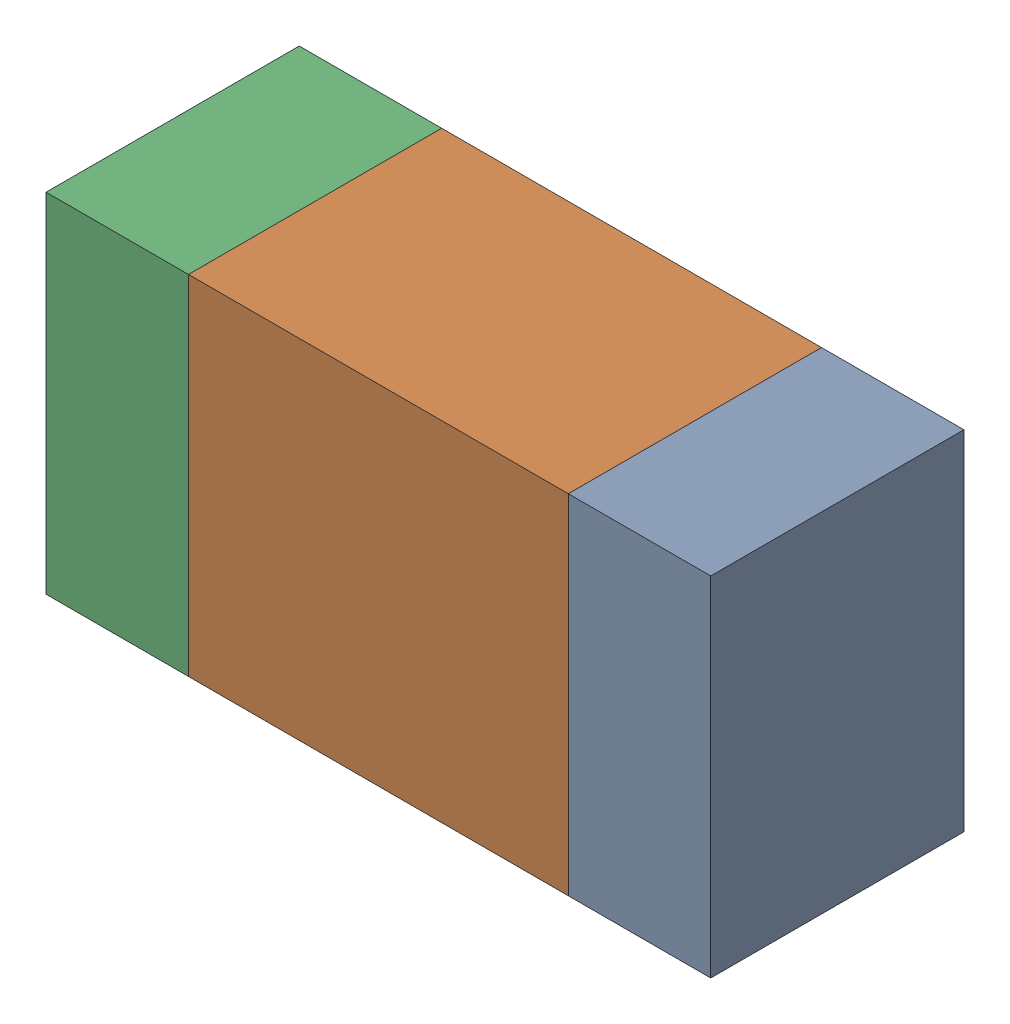
SolidWorks assembly R315_1PCB, configuration Default. Lengths in mm.
Overall size (1.05 0.55 0.4).
6 component instances, 2 part files, 0 mates.
Components (placement in the parent):
- 854785432-1: 854785432 [Default] at (134.2126 109.4999 -2.0638) size (0.22 0.55 0.4)
  - Extruded-1: Extruded [Default] at origin size (0.22 0.55 0.4)
- 854785568-1: 854785568 [Default] at (133.8001 109.4999 -2.0638) size (0.6 0.55 0.4)
  - Extruded_2-1: Extruded_2 [Default] at origin size (0.6 0.55 0.4)
- 854785432-2: 854785432 [Default] at (133.3876 109.4999 -2.0638) size (0.22 0.55 0.4)
  - Extruded-1: Extruded [Default] at origin size (0.22 0.55 0.4)
